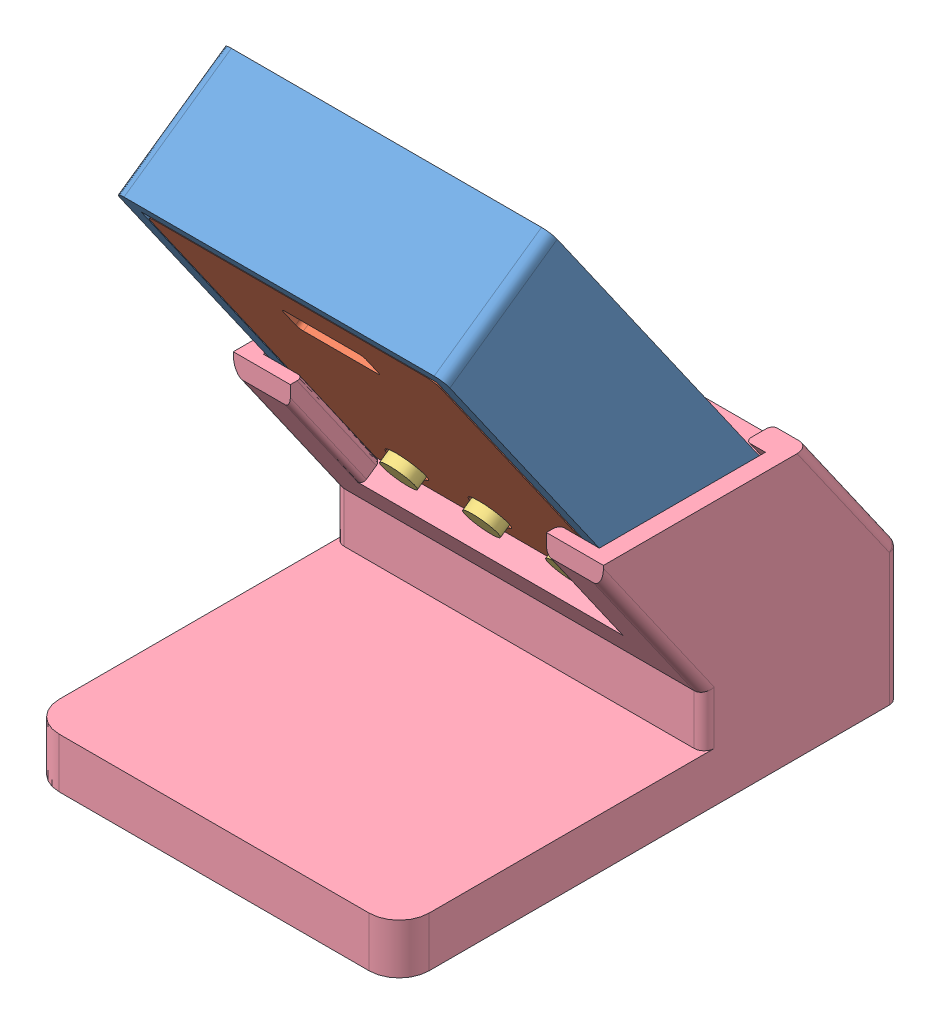
SolidWorks assembly 底座装配体, configuration 默认. Lengths in mm.
Overall size (37 56.05 50).
6 component instances, 4 part files, 16 mates.
Components (placement in the parent):
- 屏幕前壳-1: 屏幕前壳 [默认] at (74.7935 -1.796 -4.3486) x (-1 0 0) z (0 0.573576 -0.819152) size (33 44 13.1)
- 屏幕后壳-1: 屏幕后壳 [默认] at (43.7435 0.9895 -4.8398) x (1 0 0) z (0 -0.573576 0.819152) size (30.6 40 5.5)
- 按钮-1: 按钮 [默认] at (58.2435 6.3962 -3.4955) x (0.474171 0.721208 0.504996) z (0.880433 -0.388418 -0.271973) size (5.5 5 5.5)
- 底座-1: 底座 [默认] at (39.4935 -14.2866 27.0906) size (37 26.38 50)
- 按钮-2: 按钮 [默认] at (49.9435 6.3962 -3.4955) x (-0.788484 -0.503824 -0.352781) z (-0.615056 0.645888 0.452256) size (5.5 5 5.5)
- 按钮-3: 按钮 [默认] at (66.5435 6.3962 -3.4955) x (-0.788484 -0.503824 -0.352781) z (-0.615056 0.645888 0.452256) size (5.5 5 5.5)
Mates (geometry in assembly coordinates):
- 距离2: distance = 0.3 mm anti-aligned: plane of 屏幕前壳-1 through (73.0935 39.1635 10.903) normal (0 -0.819152 -0.573576); plane of 屏幕后壳-1 through (43.7435 32.6084 19.7416) normal (0 0.819152 0.573576)
- 平行1: parallel anti-aligned: plane of 屏幕前壳-1 through (43.4935 39.1635 10.903) normal (1 0 0); plane of 屏幕后壳-1 through (43.7435 -0.1577 -3.2015) normal (-1 0 0)
- 距离1: distance = 0.25 mm anti-aligned: plane of 屏幕前壳-1 through (43.4935 39.1635 10.903) normal (1 0 0); plane of 屏幕后壳-1 through (43.7435 -0.1577 -3.2015) normal (-1 0 0)
- LimitDistance1: limit distance = 0 mm aligned: plane of 屏幕后壳-1 through (43.7435 -0.1577 -3.2015) normal (0 -0.573576 0.819152); plane of 屏幕前壳-1 through (74.7935 -1.796 -4.3486) normal (0 -0.573576 0.819152)
- 同心1: concentric anti-aligned: cylinder of 屏幕后壳-1 through (58.2435 7.2566 -4.7242) axis (0 -0.573576 0.819152) radius 1.9; cylinder of 按钮-1 through (58.2435 3.5283 0.6003) axis (0 0.573576 -0.819152) radius 1.65
- 重合4: coincident anti-aligned: plane of 屏幕后壳-1 through (58.2435 5.8226 -2.6763) normal (0 0.573576 -0.819152); plane of 按钮-1 through (58.2435 5.8226 -2.6763) normal (0 -0.573576 0.819152)
- 平行3: parallel anti-aligned: plane of 屏幕前壳-1 through (74.7935 5.3737 -14.588) normal (0 -0.819152 -0.573576); plane of 底座-1 through (39.4935 -17.8098 24.6236) normal (0 0.819152 0.573576)
- LimitDistance2: limit distance = 0 mm anti-aligned: plane of 屏幕前壳-1 through (74.7935 5.3737 -14.588) normal (0 -0.819152 -0.573576); plane of 底座-1 through (39.4935 -20.6769 22.616) normal (0 0.819152 0.573576)
- 重合5: coincident anti-aligned: plane of 屏幕前壳-1 through (74.7935 -1.796 -4.3486) normal (0 -0.573576 0.819152); plane of 底座-1 through (41.1935 1.071 -2.3411) normal (0 0.573576 -0.819152)
- 重合6: coincident anti-aligned: plane of 屏幕前壳-1 through (74.7935 5.3737 -14.588) normal (1 0 0); plane of 底座-1 through (74.7935 8.8717 -13.4816) normal (-1 0 0)
- 同心2: concentric aligned: circle of 屏幕后壳-1; circle of 按钮-3
- 同心3: concentric aligned: circle of 屏幕后壳-1; circle of 按钮-2
- 重合7: coincident anti-aligned: plane of 屏幕后壳-1 through (66.5435 5.8226 -2.6763) normal (0 0.573576 -0.819152); plane of 按钮-3 through (66.5435 5.8226 -2.6763) normal (0 -0.573576 0.819152)
- 重合8: coincident anti-aligned: plane of 屏幕后壳-1 through (49.9435 5.8226 -2.6763) normal (0 0.573576 -0.819152); plane of 按钮-2 through (49.9435 5.8226 -2.6763) normal (0 -0.573576 0.819152)
- 平行5: parallel aligned: plane of 屏幕前壳-1 through (74.7935 -1.796 -4.3486) normal (0 -0.573576 0.819152); plane of 屏幕后壳-1 through (43.7435 -0.1577 -3.2015) normal (0 -0.573576 0.819152)
- 重合9: coincident aligned: plane of 屏幕前壳-1 through (74.7935 -1.796 -4.3486) normal (0 -0.573576 0.819152); plane of 屏幕后壳-1 through (43.7435 -0.1577 -3.2015) normal (0 -0.573576 0.819152)
